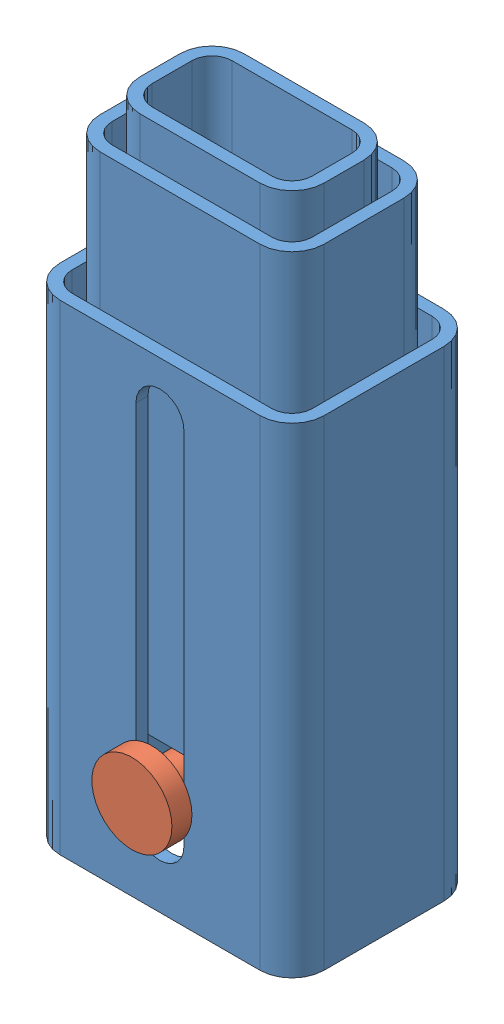
SolidWorks assembly Assem boxes, configuration Default. Lengths in mm.
Overall size (66 160.31 60).
4 component instances, 2 part files, 10 mates.
Components (placement in the parent):
- large-1: large [Default] at (56.1864 74.518 78.0164) size (66 120 46)
- large-2: large [small] at (56.1864 114.8248 78.0164) size (46 120 26)
- large-4: large [medium] at (56.1864 106.6109 78.0164) size (56 120 36)
- pin-1: pin [Default] at (56.1864 41.6109 53.0164) x (0.82923 0.558908 0) z (0.558908 -0.82923 0) size (20 60 20)
Mates (geometry in assembly coordinates):
- Width1: width aligned: plane of large-1 through (31.1864 134.518 58.0164) normal (0 0 1); plane of large-4 through (31.1864 134.518 98.0164) normal (0 0 -1); plane of large-1 through (36.1864 166.6109 96.0164) normal (0 0 1); plane of large-4 through (36.1864 166.6109 60.0164) normal (0 0 -1)
- Width2: width anti-aligned: plane of large-4 through (36.1864 166.6109 93.0164) normal (0 0 -1); plane of large-4 through (36.1864 166.6109 63.0164) normal (0 0 1); plane of large-2 through (41.1864 174.8248 91.0164) normal (0 0 1); plane of large-2 through (41.1864 174.8248 65.0164) normal (0 0 -1)
- Width3: width anti-aligned: plane of large-1 through (86.1864 134.518 63.0164) normal (-1 0 0); plane of large-1 through (26.1864 134.518 63.0164) normal (1 0 0); plane of large-4 through (84.1864 166.6109 68.0164) normal (1 0 0); plane of large-4 through (28.1864 166.6109 68.0164) normal (-1 0 0)
- Width4: width anti-aligned: plane of large-4 through (81.1864 166.6109 68.0164) normal (-1 0 0); plane of large-4 through (31.1864 166.6109 68.0164) normal (1 0 0); plane of large-2 through (36.1864 174.8248 73.0164) normal (1 0 0); plane of large-2 through (76.1864 174.8248 73.0164) normal (-1 0 0)
- Slot1: slot anti-aligned: cylinder of pin-1 through (56.1864 41.6109 103.0164) axis (0 0 -1) radius 5; plane of large-1 through (50.1864 121.7842 55.0164) normal (1 0 0); cylinder of large-1 through (56.1864 121.7842 55.0164) axis (0 0 1) radius 6
- Slot2: slot anti-aligned: cylinder of pin-1 through (56.1864 41.6109 103.0164) axis (0 0 -1) radius 5; plane of large-1 through (62.1864 121.7842 55.0164) normal (-1 0 0); cylinder of large-1 through (56.1864 121.7842 55.0164) axis (0 0 1) radius 6
- Width7: width: plane of large-1 through (62.1864 121.7842 55.0164) normal (-1 0 0); plane of large-1 through (50.1864 121.7842 55.0164) normal (1 0 0); cylinder of pin-1 through (56.1864 41.6109 103.0164) axis (0 0 -1) radius 5
- Linear/Linear Coupler1: linear coupler = 1 : 2 mm: plane of large-4 through (36.1864 166.6109 68.0164) normal (0 1 0); plane of large-2 through (41.1864 174.8248 73.0164) normal (0 1 0)
- Tangent1: tangent anti-aligned: plane of large-4 through (36.1864 46.6109 68.0164) normal (0 -1 0); cylinder of pin-1 through (56.1864 41.6109 103.0164) axis (0 0 -1) radius 5
- Width8: width aligned: plane of pin-1 through (56.1864 41.6109 53.0164) normal (0 0 1); plane of large-1 through (56.1864 41.6109 103.0164) normal (0 0 -1); plane of pin-1 through (31.1864 134.518 101.0164) normal (0 0 1); plane of large-1 through (31.1864 134.518 55.0164) normal (0 0 -1)
